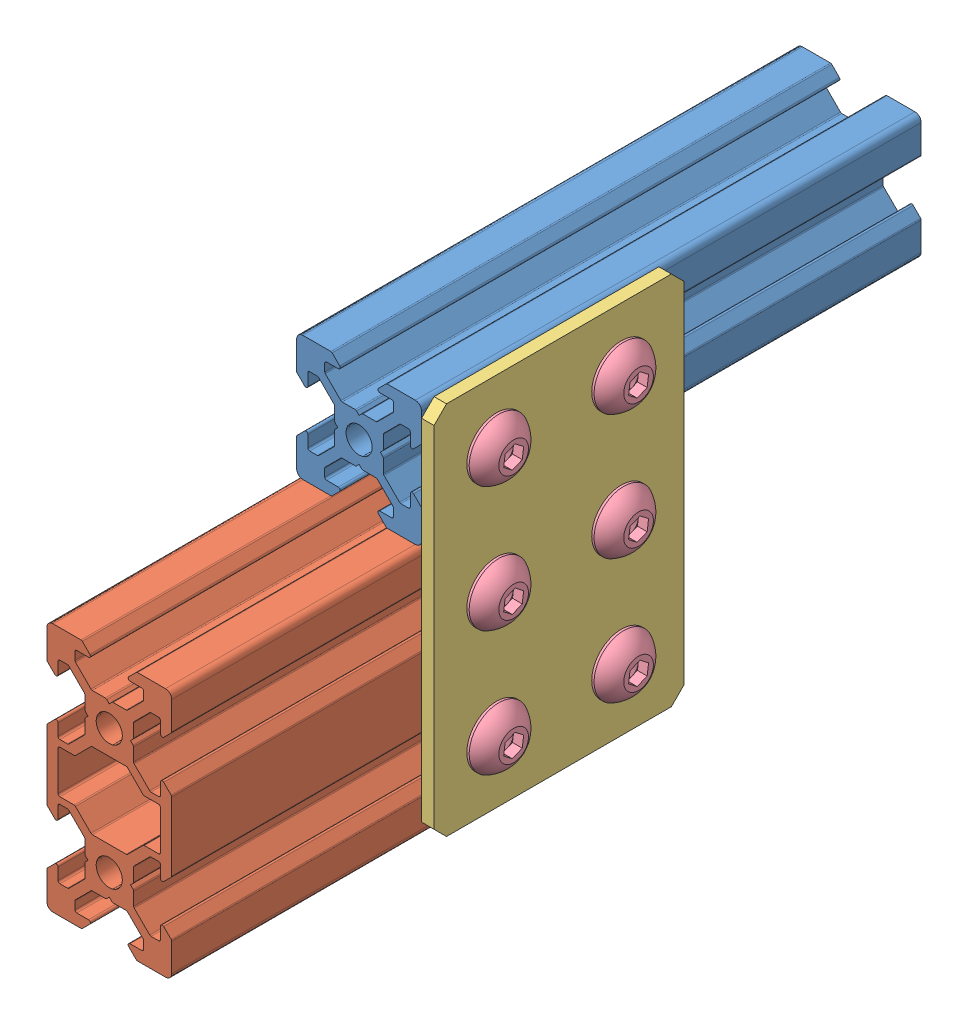
SolidWorks assembly П-Пластина 20 серия 2х3 6отв 40х60х2 СБ, configuration По умолчанию. Lengths in mm.
Overall size (24.75 60 120).
9 component instances, 4 part files, 18 mates.
Components (placement in the parent):
- 2020100-1: 2020100 [По умолчанию] at origin size (20 20 80)
- 204090-1: 204090 [По умолчанию] at (0 -20 40) x (0 -1 0) z (0 0 1) size (40 20 80)
- П-Пластина 20 серия 2х3 6отв 40х60х2-1: П-Пластина 20 серия 2х3 6отв 40х60х2 [По умолчанию] at (10 -20 60) x (0 0 -1) z (1 0 0) size (40 60 2)
- socket button head screw_iso-1: socket button head screw_iso [ISO 7380 - M5 x 10 - 10N] at (14.75 0 70) x (-1 0 0) z (0 0.924225 0.381849) size (12.75 9.5 9.5)
- socket button head screw_iso-2: socket button head screw_iso [ISO 7380 - M5 x 10 - 10N] at (14.75 0 50) x (-1 0 0) z (0 0.924225 0.381849) size (12.75 9.5 9.5)
- socket button head screw_iso-3: socket button head screw_iso [ISO 7380 - M5 x 10 - 10N] at (14.75 -20 70) x (-1 0 0) z (0 0.924225 0.381849) size (12.75 9.5 9.5)
- socket button head screw_iso-4: socket button head screw_iso [ISO 7380 - M5 x 10 - 10N] at (14.75 -20 50) x (-1 0 0) z (0 0.924225 0.381849) size (12.75 9.5 9.5)
- socket button head screw_iso-5: socket button head screw_iso [ISO 7380 - M5 x 10 - 10N] at (14.75 -40 70) x (-1 0 0) z (0 0.924225 0.381849) size (12.75 9.5 9.5)
- socket button head screw_iso-6: socket button head screw_iso [ISO 7380 - M5 x 10 - 10N] at (14.75 -40 50) x (-1 0 0) z (0 0.924225 0.381849) size (12.75 9.5 9.5)
Mates (geometry in assembly coordinates):
- Совпадение1: coincident aligned: plane of 2020100-1 through (10 -10 80) normal (1 0 0); plane of 204090-1 through (10 -10 120) normal (1 0 0)
- Совпадение2: coincident anti-aligned: plane of 2020100-1 through (-10 -10 80) normal (0 -1 0); plane of 204090-1 through (-10 -10 120) normal (0 1 0)
- Совпадение3: coincident anti-aligned: plane of 204090-1 through (10 -35.6 120) normal (1 0 0); plane of П-Пластина 20 серия 2х3 6отв 40х60х2-1 through (10 -20 60) normal (-1 0 0)
- Совпадение4: coincident aligned: plane of 204090-1 through (10 -50 120) normal (0 -1 0); plane of П-Пластина 20 серия 2х3 6отв 40х60х2-1 through (12 -50 80) normal (0 -1 0)
- Совпадение5: coincident aligned: plane of 204090-1 through (0 -20 40) normal (0 0 -1); plane of П-Пластина 20 серия 2х3 6отв 40х60х2-1 through (12 -50 40) normal (0 0 -1)
- Совпадение6: coincident aligned: plane of 2020100-1 through (0 0 80) normal (0 0 1); plane of П-Пластина 20 серия 2х3 6отв 40х60х2-1 through (12 -50 80) normal (0 0 1)
- Концентричный1: concentric aligned: cylinder of П-Пластина 20 серия 2х3 6отв 40х60х2-1 through (12 0 70) axis (1 0 0) radius 2.75; cylinder of socket button head screw_iso-1 through (14.75 0 70) axis (1 0 0) radius 4.75
- Совпадение7: coincident anti-aligned: plane of П-Пластина 20 серия 2х3 6отв 40х60х2-1 through (12 -20 60) normal (1 0 0); plane of socket button head screw_iso-1 through (12 -0.9546 72.3106) normal (-1 0 0)
- Концентричный2: concentric aligned: cylinder of П-Пластина 20 серия 2х3 6отв 40х60х2-1 through (12 0 50) axis (1 0 0) radius 2.75; cylinder of socket button head screw_iso-2 through (14.75 0 50) axis (1 0 0) radius 4.75
- Совпадение8: coincident anti-aligned: plane of П-Пластина 20 серия 2х3 6отв 40х60х2-1 through (12 -20 60) normal (1 0 0); plane of socket button head screw_iso-2 through (12 -0.9546 52.3106) normal (-1 0 0)
- Концентричный3: concentric aligned: cylinder of П-Пластина 20 серия 2х3 6отв 40х60х2-1 through (12 -20 70) axis (1 0 0) radius 2.75; cylinder of socket button head screw_iso-3 through (14.75 -20 70) axis (1 0 0) radius 4.75
- Совпадение9: coincident anti-aligned: plane of П-Пластина 20 серия 2х3 6отв 40х60х2-1 through (12 -20 60) normal (1 0 0); plane of socket button head screw_iso-3 through (12 -20.9546 72.3106) normal (-1 0 0)
- Концентричный4: concentric aligned: cylinder of П-Пластина 20 серия 2х3 6отв 40х60х2-1 through (12 -20 50) axis (1 0 0) radius 2.75; cylinder of socket button head screw_iso-4 through (14.75 -20 50) axis (1 0 0) radius 4.75
- Совпадение10: coincident anti-aligned: plane of П-Пластина 20 серия 2х3 6отв 40х60х2-1 through (12 -20 60) normal (1 0 0); plane of socket button head screw_iso-4 through (12 -20.9546 52.3106) normal (-1 0 0)
- Концентричный5: concentric aligned: cylinder of П-Пластина 20 серия 2х3 6отв 40х60х2-1 through (12 -40 70) axis (1 0 0) radius 2.75; cylinder of socket button head screw_iso-5 through (14.75 -40 70) axis (1 0 0) radius 4.75
- Совпадение11: coincident anti-aligned: plane of П-Пластина 20 серия 2х3 6отв 40х60х2-1 through (12 -20 60) normal (1 0 0); plane of socket button head screw_iso-5 through (12 -40.9546 72.3106) normal (-1 0 0)
- Концентричный6: concentric aligned: cylinder of П-Пластина 20 серия 2х3 6отв 40х60х2-1 through (12 -40 50) axis (1 0 0) radius 2.75; cylinder of socket button head screw_iso-6 through (14.75 -40 50) axis (1 0 0) radius 4.75
- Совпадение12: coincident anti-aligned: plane of П-Пластина 20 серия 2х3 6отв 40х60х2-1 through (12 -20 60) normal (1 0 0); plane of socket button head screw_iso-6 through (12 -40.9546 52.3106) normal (-1 0 0)
